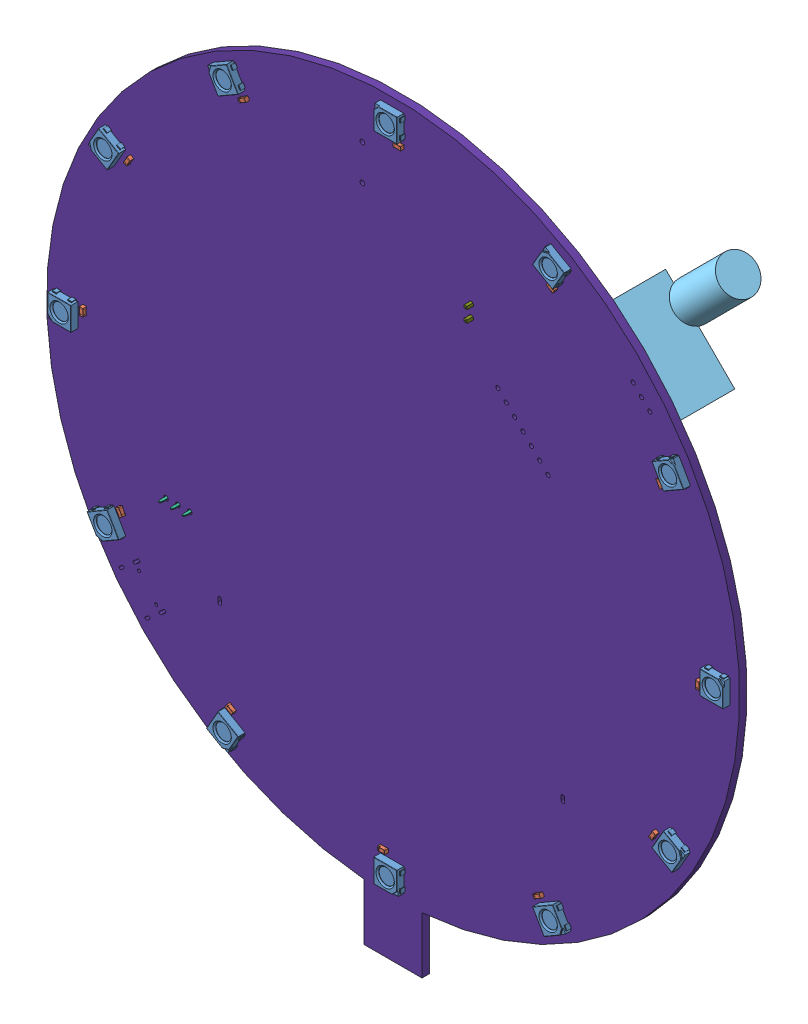
SolidWorks assembly Semafor, configuration Výchozí. Lengths in mm.
Overall size (148.79 160.68 22.8).
168 component instances, 17 part files, 0 mates.
Components (placement in the parent):
- Semafor.step-1: Semafor.step [Výchozí] at origin size (148.79 160.68 22.8)
  - LED_WS2812B_PLCC4_5.0x5.0mm_P3.2mm.step-1: LED_WS2812B_PLCC4_5.0x5.0mm_P3.2mm.step [Výchozí] at (-39.4282 65.1 1.65) x (0.5 0.866025 0) z (0 0 1) size (5.4 5 1.6)
    - SOLID.step-1: SOLID.step [Výchozí] at origin size (5.4 5 1.6)
  - LED_WS2812B_PLCC4_5.0x5.0mm_P3.2mm.step-2: LED_WS2812B_PLCC4_5.0x5.0mm_P3.2mm.step [Výchozí] at (-30.05 100.1 1.65) x (0 1 0) z (0 0 1) size (5.4 5 1.6)
    - SOLID.step-1: SOLID.step [Výchozí] at origin size (5.4 5 1.6)
  - LED_WS2812B_PLCC4_5.0x5.0mm_P3.2mm.step-3: LED_WS2812B_PLCC4_5.0x5.0mm_P3.2mm.step [Výchozí] at (-170.05 100.1 1.65) x (0 -1 0) z (0 0 1) size (5.4 5 1.6)
    - SOLID.step-1: SOLID.step [Výchozí] at origin size (5.4 5 1.6)
  - C_0603_1608Metric.step-1: C_0603_1608Metric.step [Výchozí] at (-101.75 33.8 1.65) size (1.6 0.8 0.8)
    - SOLID-0.step-1: SOLID-0.step [Výchozí] at origin size (1.6 0.8 0.8)
  - C_0603_1608Metric.step-2: C_0603_1608Metric.step [Výchozí] at (-43.5875 65.6288 1.65) x (0.5 0.866025 0) z (0 0 1) size (1.6 0.8 0.8)
    - SOLID-0.step-1: SOLID-0.step [Výchozí] at origin size (1.6 0.8 0.8)
  - C_0603_1608Metric.step-3: C_0603_1608Metric.step [Výchozí] at (-134.4288 43.6125 1.65) x (0.866025 -0.5 0) z (0 0 1) size (1.6 0.8 0.8)
    - SOLID-0.step-1: SOLID-0.step [Výchozí] at origin size (1.6 0.8 0.8)
  - C_0603_1608Metric.step-4: C_0603_1608Metric.step [Výchozí] at (-166.15 101.75 1.65) x (0 -1 0) z (0 0 1) size (1.6 0.8 0.8)
    - SOLID-0.step-1: SOLID-0.step [Výchozí] at origin size (1.6 0.8 0.8)
  - LED_WS2812B_PLCC4_5.0x5.0mm_P3.2mm.step-4: LED_WS2812B_PLCC4_5.0x5.0mm_P3.2mm.step [Výchozí] at (-100.05 30.1 1.65) size (5.4 5 1.6)
    - SOLID.step-1: SOLID.step [Výchozí] at origin size (5.4 5 1.6)
  - C_0603_1608Metric.step-5: C_0603_1608Metric.step [Výchozí] at (-158.05 68.5 1.65) x (0.5 -0.866025 0) z (0 0 1) size (1.6 0.8 0.8)
    - SOLID-0.step-1: SOLID-0.step [Výchozí] at origin size (1.6 0.8 0.8)
  - C_0603_1608Metric.step-6: C_0603_1608Metric.step [Výchozí] at (-68.35 41.95 1.65) x (0.866025 0.5 0) z (0 0 1) size (1.6 0.8 0.8)
    - SOLID-0.step-1: SOLID-0.step [Výchozí] at origin size (1.6 0.8 0.8)
  - LED_WS2812B_PLCC4_5.0x5.0mm_P3.2mm.step-5: LED_WS2812B_PLCC4_5.0x5.0mm_P3.2mm.step [Výchozí] at (-100.05 170.1 1.65) x (-1 0 0) z (0 0 1) size (5.4 5 1.6)
    - SOLID.step-1: SOLID.step [Výchozí] at origin size (5.4 5 1.6)
  - LED_WS2812B_PLCC4_5.0x5.0mm_P3.2mm.step-6: LED_WS2812B_PLCC4_5.0x5.0mm_P3.2mm.step [Výchozí] at (-39.4282 135.1 1.65) x (-0.5 0.866025 0) z (0 0 1) size (5.4 5 1.6)
    - SOLID.step-1: SOLID.step [Výchozí] at origin size (5.4 5 1.6)
  - LED_WS2812B_PLCC4_5.0x5.0mm_P3.2mm.step-7: LED_WS2812B_PLCC4_5.0x5.0mm_P3.2mm.step [Výchozí] at (-160.6718 65.1 1.65) x (0.5 -0.866025 0) z (0 0 1) size (5.4 5 1.6)
    - SOLID.step-1: SOLID.step [Výchozí] at origin size (5.4 5 1.6)
  - LED_WS2812B_PLCC4_5.0x5.0mm_P3.2mm.step-8: LED_WS2812B_PLCC4_5.0x5.0mm_P3.2mm.step [Výchozí] at (-65.05 39.4782 1.65) x (0.866025 0.5 0) z (0 0 1) size (5.4 5 1.6)
    - SOLID.step-1: SOLID.step [Výchozí] at origin size (5.4 5 1.6)
  - C_0603_1608Metric.step-7: C_0603_1608Metric.step [Výchozí] at (-65.45 156.55 1.65) x (-0.866025 0.5 0) z (0 0 1) size (1.6 0.8 0.8)
    - SOLID-0.step-1: SOLID-0.step [Výchozí] at origin size (1.6 0.8 0.8)
  - C_0603_1608Metric.step-8: C_0603_1608Metric.step [Výchozí] at (-33.9 98.45 1.65) x (0 1 0) z (0 0 1) size (1.6 0.8 0.8)
    - SOLID-0.step-1: SOLID-0.step [Výchozí] at origin size (1.6 0.8 0.8)
  - C_0603_1608Metric.step-9: C_0603_1608Metric.step [Výchozí] at (-98.4 166.3 1.65) x (-1 0 0) z (0 0 1) size (1.6 0.8 0.8)
    - SOLID-0.step-1: SOLID-0.step [Výchozí] at origin size (1.6 0.8 0.8)
  - LED_WS2812B_PLCC4_5.0x5.0mm_P3.2mm.step-9: LED_WS2812B_PLCC4_5.0x5.0mm_P3.2mm.step [Výchozí] at (-160.6718 135.1 1.65) x (-0.5 -0.866025 0) z (0 0 1) size (5.4 5 1.6)
    - SOLID.step-1: SOLID.step [Výchozí] at origin size (5.4 5 1.6)
  - LED_WS2812B_PLCC4_5.0x5.0mm_P3.2mm.step-10: LED_WS2812B_PLCC4_5.0x5.0mm_P3.2mm.step [Výchozí] at (-65.05 160.7218 1.65) x (-0.866025 0.5 0) z (0 0 1) size (5.4 5 1.6)
    - SOLID.step-1: SOLID.step [Výchozí] at origin size (5.4 5 1.6)
  - C_0603_1608Metric.step-10: C_0603_1608Metric.step [Výchozí] at (-156.35 134.6 1.65) x (-0.5 -0.866025 0) z (0 0 1) size (1.6 0.8 0.8)
    - SOLID-0.step-1: SOLID-0.step [Výchozí] at origin size (1.6 0.8 0.8)
  - LED_WS2812B_PLCC4_5.0x5.0mm_P3.2mm.step-11: LED_WS2812B_PLCC4_5.0x5.0mm_P3.2mm.step [Výchozí] at (-135.05 160.7218 1.65) x (-0.866025 -0.5 0) z (0 0 1) size (5.4 5 1.6)
    - SOLID.step-1: SOLID.step [Výchozí] at origin size (5.4 5 1.6)
  - C_0603_1608Metric.step-11: C_0603_1608Metric.step [Výchozí] at (-131.65 158.3 1.65) x (-0.866025 -0.5 0) z (0 0 1) size (1.6 0.8 0.8)
    - SOLID-0.step-1: SOLID-0.step [Výchozí] at origin size (1.6 0.8 0.8)
  - C_0603_1608Metric.step-12: C_0603_1608Metric.step [Výchozí] at (-42.05 131.8 1.65) x (-0.5 0.866025 0) z (0 0 1) size (1.6 0.8 0.8)
    - SOLID-0.step-1: SOLID-0.step [Výchozí] at origin size (1.6 0.8 0.8)
  - LED_WS2812B_PLCC4_5.0x5.0mm_P3.2mm.step-12: LED_WS2812B_PLCC4_5.0x5.0mm_P3.2mm.step [Výchozí] at (-135.05 39.4782 1.65) x (0.866025 -0.5 0) z (0 0 1) size (5.4 5 1.6)
    - SOLID.step-1: SOLID.step [Výchozí] at origin size (5.4 5 1.6)
  - R_0603_1608Metric.step-1: R_0603_1608Metric.step [Výchozí] at (-119.75 147.925 -0.05) x (0 -1 0) z (0 0 -1) size (1.6 0.8 0.45)
    - SOLID-1.step-1: SOLID-1.step [Výchozí] at origin size (1.6 0.8 0.45)
  - R_0603_1608Metric.step-2: R_0603_1608Metric.step [Výchozí] at (-115.95 147.9 -0.05) x (0 -1 0) z (0 0 -1) size (1.6 0.8 0.45)
    - SOLID-1.step-1: SOLID-1.step [Výchozí] at origin size (1.6 0.8 0.45)
  - D_SOD-123.step-1: D_SOD-123.step [Výchozí] at (-130.0125 82.075 -0.05) x (-1 0 0) z (0 0 -1) size (3.8 1.6 1.25)
    - SOLID-2.step-1: SOLID-2.step [Výchozí] at origin size (3.8 1.6 1.25)
  - E22_900T22D.step-1: E22_900T22D.step [Výchozí] at (-60.45 137.7711 -0.05) x (-0.707107 -0.707107 0) z (0 0 -1) size (50 21 17.3)
    - SOLID-3.step-1: SOLID-3.step [Výchozí] at origin size (50 21 17.3)
  - D_SOD-123.step-2: D_SOD-123.step [Výchozí] at (-96.1 29.05 -0.05) x (0 -1 0) z (0 0 -1) size (3.8 1.6 1.25)
    - SOLID-2.step-1: SOLID-2.step [Výchozí] at origin size (3.8 1.6 1.25)
  - PinSocket_1x03_P2.54mm_Vertical.step-1: PinSocket_1x03_P2.54mm_Vertical.step [Výchozí] at (-143.675 75.375 -0.05) x (0 1 0) z (0 0 -1) size (2.54 7.62 10.1)
    - SOLID-4.step-1: SOLID-4.step [Výchozí] at origin size (2.54 7.62 10.1)
  - D_SOD-323.step-1: D_SOD-323.step [Výchozí] at (-142.6 58.8 -0.05) x (0.642788 -0.766044 0) z (0 0 -1) size (2.5 1.25 1.1)
    - SOLID-5.step-1: SOLID-5.step [Výchozí] at origin size (2.5 1.25 1.1)
  - C_0603_1608Metric.step-13: C_0603_1608Metric.step [Výchozí] at (-158.9591 131.0993 -0.05) x (-0.939693 0.34202 0) z (0 0 -1) size (1.6 0.8 0.8)
    - SOLID-0.step-1: SOLID-0.step [Výchozí] at origin size (1.6 0.8 0.8)
  - R_0603_1608Metric.step-3: R_0603_1608Metric.step [Výchozí] at (-83.3756 132.275 -0.05) x (-1 0 0) z (0 0 -1) size (1.6 0.8 0.45)
    - SOLID-1.step-1: SOLID-1.step [Výchozí] at origin size (1.6 0.8 0.45)
  - R_0603_1608Metric.step-4: R_0603_1608Metric.step [Výchozí] at (-118.05 147.9 -0.05) x (0 -1 0) z (0 0 -1) size (1.6 0.8 0.45)
    - SOLID-1.step-1: SOLID-1.step [Výchozí] at origin size (1.6 0.8 0.45)
  - R_0603_1608Metric.step-5: R_0603_1608Metric.step [Výchozí] at (-116.95 136.3 -0.05) x (0 -1 0) z (0 0 -1) size (1.6 0.8 0.45)
    - SOLID-1.step-1: SOLID-1.step [Výchozí] at origin size (1.6 0.8 0.45)
  - C_0805_2012Metric.step-1: C_0805_2012Metric.step [Výchozí] at (-152.9591 126.5493 -0.05) x (0.939693 -0.34202 0) z (0 0 -1) size (2 1.25 1.25)
    - SOLID-6.step-1: SOLID-6.step [Výchozí] at origin size (2 1.25 1.25)
  - LED_0603_1608Metric.step-1: LED_0603_1608Metric.step [Výchozí] at (-147.525 84.025 -0.05) x (-1 0 0) z (0 0 -1) size (1.6 0.8 1.1)
    - SOLID-7.step-1: SOLID-7.step [Výchozí] at origin size (1.6 0.8 1.1)
  - SOT-23.step-1: SOT-23.step [Výchozí] at (-83.3256 136.55 -0.05) x (0 1 0) z (0 0 -1) size (2.5 3 1.2)
    - SOLID-8.step-1: SOLID-8.step [Výchozí] at origin size (2.5 3 1.2)
  - SOT-23.step-2: SOT-23.step [Výchozí] at (-146.9091 122.0993 -0.05) x (0.939693 -0.34202 0) z (0 0 -1) size (2.5 3 1.2)
    - SOLID-8.step-1: SOLID-8.step [Výchozí] at origin size (2.5 3 1.2)
  - R_0603_1608Metric.step-6: R_0603_1608Metric.step [Výchozí] at (-120.725 43.975 -0.05) x (-1 0 0) z (0 0 -1) size (1.6 0.8 0.45)
    - SOLID-1.step-1: SOLID-1.step [Výchozí] at origin size (1.6 0.8 0.45)
  - C_0805_2012Metric.step-2: C_0805_2012Metric.step [Výchozí] at (-159.7591 129.0993 -0.05) x (-0.939693 0.34202 0) z (0 0 -1) size (2 1.25 1.25)
    - SOLID-6.step-1: SOLID-6.step [Výchozí] at origin size (2 1.25 1.25)
  - R_0603_1608Metric.step-7: R_0603_1608Metric.step [Výchozí] at (-120.15 136.3 -0.05) x (0 -1 0) z (0 0 -1) size (1.6 0.8 0.45)
    - SOLID-1.step-1: SOLID-1.step [Výchozí] at origin size (1.6 0.8 0.45)
  - D_SOD-323.step-2: D_SOD-323.step [Výchozí] at (-147.5 62.875 -0.05) x (-0.766044 -0.642788 0) z (0 0 -1) size (2.5 1.25 1.1)
    - SOLID-5.step-1: SOLID-5.step [Výchozí] at origin size (2.5 1.25 1.1)
  - C_0805_2012Metric.step-3: C_0805_2012Metric.step [Výchozí] at (-128.3875 78.75 -0.05) x (0 -1 0) z (0 0 -1) size (2 1.25 1.25)
    - SOLID-6.step-1: SOLID-6.step [Výchozí] at origin size (2 1.25 1.25)
  - R_0603_1608Metric.step-8: R_0603_1608Metric.step [Výchozí] at (-143.0091 117.4493 -0.05) x (0.939693 -0.34202 0) z (0 0 -1) size (1.6 0.8 0.45)
    - SOLID-1.step-1: SOLID-1.step [Výchozí] at origin size (1.6 0.8 0.45)
  - LED_0603_1608Metric.step-2: LED_0603_1608Metric.step [Výchozí] at (-109.425 43.2125 -0.05) x (0 -1 0) z (0 0 -1) size (1.6 0.8 1.1)
    - SOLID-7.step-1: SOLID-7.step [Výchozí] at origin size (1.6 0.8 1.1)
  - R_0603_1608Metric.step-9: R_0603_1608Metric.step [Výchozí] at (-135.1875 77.025 -0.05) x (0 1 0) z (0 0 -1) size (1.6 0.8 0.45)
    - SOLID-1.step-1: SOLID-1.step [Výchozí] at origin size (1.6 0.8 0.45)
  - USB_C.step-1: USB_C.step [Výchozí] at (-154.7 55.1 -0.05) x (-0.766044 -0.642788 0) z (0 0 -1) size (7.5 9 3.5)
    - SOLID-9.step-1: SOLID-9.step [Výchozí] at origin size (7.5 9 3.5)
  - Battery_pack.step-1: Battery_pack.step [Výchozí] at (-99.9 62.1 -0.05) x (-1 0 0) z (0 0 -1) size (77 21 19.5)
    - SOLID-10.step-1: SOLID-10.step [Výchozí] at origin size (77 21 19.5)
  - LED_0603_1608Metric.step-3: LED_0603_1608Metric.step [Výchozí] at (-107.575 43.225 -0.05) x (0 -1 0) z (0 0 -1) size (1.6 0.8 1.1)
    - SOLID-7.step-1: SOLID-7.step [Výchozí] at origin size (1.6 0.8 1.1)
  - R_0603_1608Metric.step-10: R_0603_1608Metric.step [Výchozí] at (-144.1125 87.05 -0.05) x (1 0 0) z (0 0 -1) size (1.6 0.8 0.45)
    - SOLID-1.step-1: SOLID-1.step [Výchozí] at origin size (1.6 0.8 0.45)
  - D_SOD-123.step-3: D_SOD-123.step [Výchozí] at (-117.975 155.17 -0.05) x (-1 0 0) z (0 0 -1) size (3.8 1.6 1.25)
    - SOLID-2.step-1: SOLID-2.step [Výchozí] at origin size (3.8 1.6 1.25)
  - R_0603_1608Metric.step-11: R_0603_1608Metric.step [Výchozí] at (-114.175 160.345 -0.05) x (0 -1 0) z (0 0 -1) size (1.6 0.8 0.45)
    - SOLID-1.step-1: SOLID-1.step [Výchozí] at origin size (1.6 0.8 0.45)
  - R_0603_1608Metric.step-12: R_0603_1608Metric.step [Výchozí] at (-150.9091 118.3743 -0.05) x (-0.34202 -0.939693 0) z (0 0 -1) size (1.6 0.8 0.45)
    - SOLID-1.step-1: SOLID-1.step [Výchozí] at origin size (1.6 0.8 0.45)
  - D_SOD-323.step-3: D_SOD-323.step [Výchozí] at (-98.4 29.65 -0.05) x (0 1 0) z (0 0 -1) size (2.5 1.25 1.1)
    - SOLID-5.step-1: SOLID-5.step [Výchozí] at origin size (2.5 1.25 1.1)
  - SOIC-14_3.9x8.7mm_P1.27mm.step-1: SOIC-14_3.9x8.7mm_P1.27mm.step [Výchozí] at (-118.5 142.1 -0.05) x (0 -1 0) z (0 0 -1) size (6 8.7 1.75)
    - SOLID-11.step-1: SOLID-11.step [Výchozí] at origin size (6 8.7 1.75)
  - C_0603_1608Metric.step-14: C_0603_1608Metric.step [Výchozí] at (-124.55 142.3493 -0.05) x (0 -1 0) z (0 0 -1) size (1.6 0.8 0.8)
    - SOLID-0.step-1: SOLID-0.step [Výchozí] at origin size (1.6 0.8 0.8)
  - R_0603_1608Metric.step-13: R_0603_1608Metric.step [Výchozí] at (-147.4841 125.4493 -0.05) x (0.939693 -0.34202 0) z (0 0 -1) size (1.6 0.8 0.45)
    - SOLID-1.step-1: SOLID-1.step [Výchozí] at origin size (1.6 0.8 0.45)
  - C_0805_2012Metric.step-4: C_0805_2012Metric.step [Výchozí] at (-126.5 142.3993 -0.05) x (0 -1 0) z (0 0 -1) size (2 1.25 1.25)
    - SOLID-6.step-1: SOLID-6.step [Výchozí] at origin size (2 1.25 1.25)
  - R_0603_1608Metric.step-14: R_0603_1608Metric.step [Výchozí] at (-139.1625 81.2 -0.05) x (0 -1 0) z (0 0 -1) size (1.6 0.8 0.45)
    - SOLID-1.step-1: SOLID-1.step [Výchozí] at origin size (1.6 0.8 0.45)
  - R_0603_1608Metric.step-15: R_0603_1608Metric.step [Výchozí] at (-132.6875 77.875 -0.05) x (1 0 0) z (0 0 -1) size (1.6 0.8 0.45)
    - SOLID-1.step-1: SOLID-1.step [Výchozí] at origin size (1.6 0.8 0.45)
  - SOT-23.step-3: SOT-23.step [Výchozí] at (-118.675 160.445 -0.05) x (-1 0 0) z (0 0 -1) size (2.5 3 1.2)
    - SOLID-8.step-1: SOLID-8.step [Výchozí] at origin size (2.5 3 1.2)
  - R_0402_1005Metric.step-1: R_0402_1005Metric.step [Výchozí] at (-150.45 61 -0.05) x (0.766044 0.642788 0) z (0 0 -1) size (1 0.5 0.35)
    - SOLID-12.step-1: SOLID-12.step [Výchozí] at origin size (1 0.5 0.35)
  - C_0805_2012Metric.step-5: C_0805_2012Metric.step [Výchozí] at (-114.675 48.525 -0.05) x (-1 0 0) z (0 0 -1) size (2 1.25 1.25)
    - SOLID-6.step-1: SOLID-6.step [Výchozí] at origin size (2 1.25 1.25)
  - R_0603_1608Metric.step-16: R_0603_1608Metric.step [Výchozí] at (-152.1341 114.7493 -0.05) x (-0.34202 -0.939693 0) z (0 0 -1) size (1.6 0.8 0.45)
    - SOLID-1.step-1: SOLID-1.step [Výchozí] at origin size (1.6 0.8 0.45)
  - C_0603_1608Metric.step-15: C_0603_1608Metric.step [Výchozí] at (-78.4756 143.175 -0.05) x (0 -1 0) z (0 0 -1) size (1.6 0.8 0.8)
    - SOLID-0.step-1: SOLID-0.step [Výchozí] at origin size (1.6 0.8 0.8)
  - C_0805_2012Metric.step-6: C_0805_2012Metric.step [Výchozí] at (-120.625 46.525 -0.05) x (-1 0 0) z (0 0 -1) size (2 1.25 1.25)
    - SOLID-6.step-1: SOLID-6.step [Výchozí] at origin size (2 1.25 1.25)
  - R_0603_1608Metric.step-17: R_0603_1608Metric.step [Výchozí] at (-115.3 136.3 -0.05) x (0 1 0) z (0 0 -1) size (1.6 0.8 0.45)
    - SOLID-1.step-1: SOLID-1.step [Výchozí] at origin size (1.6 0.8 0.45)
  - SOT-23-5.step-1: SOT-23-5.step [Výchozí] at (-135.2875 81.1 -0.05) x (-1 0 0) z (0 0 -1) size (2.8 2.9 1.55)
    - SOLID-13.step-1: SOLID-13.step [Výchozí] at origin size (2.8 2.9 1.55)
  - R_0402_1005Metric.step-2: R_0402_1005Metric.step [Výchozí] at (-148.35 58.75 -0.05) x (0.766044 0.642788 0) z (0 0 -1) size (1 0.5 0.35)
    - SOLID-12.step-1: SOLID-12.step [Výchozí] at origin size (1 0.5 0.35)
  - C_0805_2012Metric.step-7: C_0805_2012Metric.step [Výchozí] at (-136.7875 84.075 -0.05) x (1 0 0) z (0 0 -1) size (2 1.25 1.25)
    - SOLID-6.step-1: SOLID-6.step [Výchozí] at origin size (2 1.25 1.25)
  - PinHeader_1x02_P2.54mm_Vertical.step-1: PinHeader_1x02_P2.54mm_Vertical.step [Výchozí] at (-83.2244 144.25 -0.05) x (-1 0 0) z (0 0 -1) size (2.54 5.08 11.54)
    - SOLID-14.step-1: SOLID-14.step [Výchozí] at origin size (2.54 5.08 11.54)
  - D_SOD-323.step-4: D_SOD-323.step [Výchozí] at (-146.2 61.275 -0.05) x (-0.766044 -0.642788 0) z (0 0 -1) size (2.5 1.25 1.1)
    - SOLID-5.step-1: SOLID-5.step [Výchozí] at origin size (2.5 1.25 1.1)
  - LED_0603_1608Metric.step-4: LED_0603_1608Metric.step [Výchozí] at (-147.5125 87.075 -0.05) x (-1 0 0) z (0 0 -1) size (1.6 0.8 1.1)
    - SOLID-7.step-1: SOLID-7.step [Výchozí] at origin size (1.6 0.8 1.1)
  - R_0603_1608Metric.step-18: R_0603_1608Metric.step [Výchozí] at (-156.1591 128.8493 -0.05) x (0.939693 -0.34202 0) z (0 0 -1) size (1.6 0.8 0.45)
    - SOLID-1.step-1: SOLID-1.step [Výchozí] at origin size (1.6 0.8 0.45)
  - R_0603_1608Metric.step-19: R_0603_1608Metric.step [Výchozí] at (-144.15 84.05 -0.05) x (1 0 0) z (0 0 -1) size (1.6 0.8 0.45)
    - SOLID-1.step-1: SOLID-1.step [Výchozí] at origin size (1.6 0.8 0.45)
  - R_0603_1608Metric.step-20: R_0603_1608Metric.step [Výchozí] at (-110.275 40.775 -0.05) x (1 0 0) z (0 0 -1) size (1.6 0.8 0.45)
    - SOLID-1.step-1: SOLID-1.step [Výchozí] at origin size (1.6 0.8 0.45)
  - D_SOD-123.step-4: D_SOD-123.step [Výchozí] at (-144.6 55.65 -0.05) x (-0.766044 -0.642788 0) z (0 0 -1) size (3.8 1.6 1.25)
    - SOLID-2.step-1: SOLID-2.step [Výchozí] at origin size (3.8 1.6 1.25)
  - SOT-23.step-4: SOT-23.step [Výchozí] at (-143.8591 114.7993 -0.05) x (0.939693 -0.34202 0) z (0 0 -1) size (2.5 3 1.2)
    - SOLID-8.step-1: SOLID-8.step [Výchozí] at origin size (2.5 3 1.2)
  - R_0603_1608Metric.step-21: R_0603_1608Metric.step [Výchozí] at (-155.1091 131.9243 -0.05) x (-0.34202 -0.939693 0) z (0 0 -1) size (1.6 0.8 0.45)
    - SOLID-1.step-1: SOLID-1.step [Výchozí] at origin size (1.6 0.8 0.45)
  - R_0603_1608Metric.step-22: R_0603_1608Metric.step [Výchozí] at (-118.55 136.3 -0.05) x (0 -1 0) z (0 0 -1) size (1.6 0.8 0.45)
    - SOLID-1.step-1: SOLID-1.step [Výchozí] at origin size (1.6 0.8 0.45)
  - R_0603_1608Metric.step-23: R_0603_1608Metric.step [Výchozí] at (-121.75 136.2993 -0.05) x (0 -1 0) z (0 0 -1) size (1.6 0.8 0.45)
    - SOLID-1.step-1: SOLID-1.step [Výchozí] at origin size (1.6 0.8 0.45)
  - D_SOD-123.step-5: D_SOD-123.step [Výchozí] at (-74.5506 143.175 -0.05) x (0 -1 0) z (0 0 -1) size (3.8 1.6 1.25)
    - SOLID-2.step-1: SOLID-2.step [Výchozí] at origin size (3.8 1.6 1.25)
  - Semafor PCB.step-1: Semafor PCB.step [Výchozí] at origin size (148.79 160.68 1.6)
